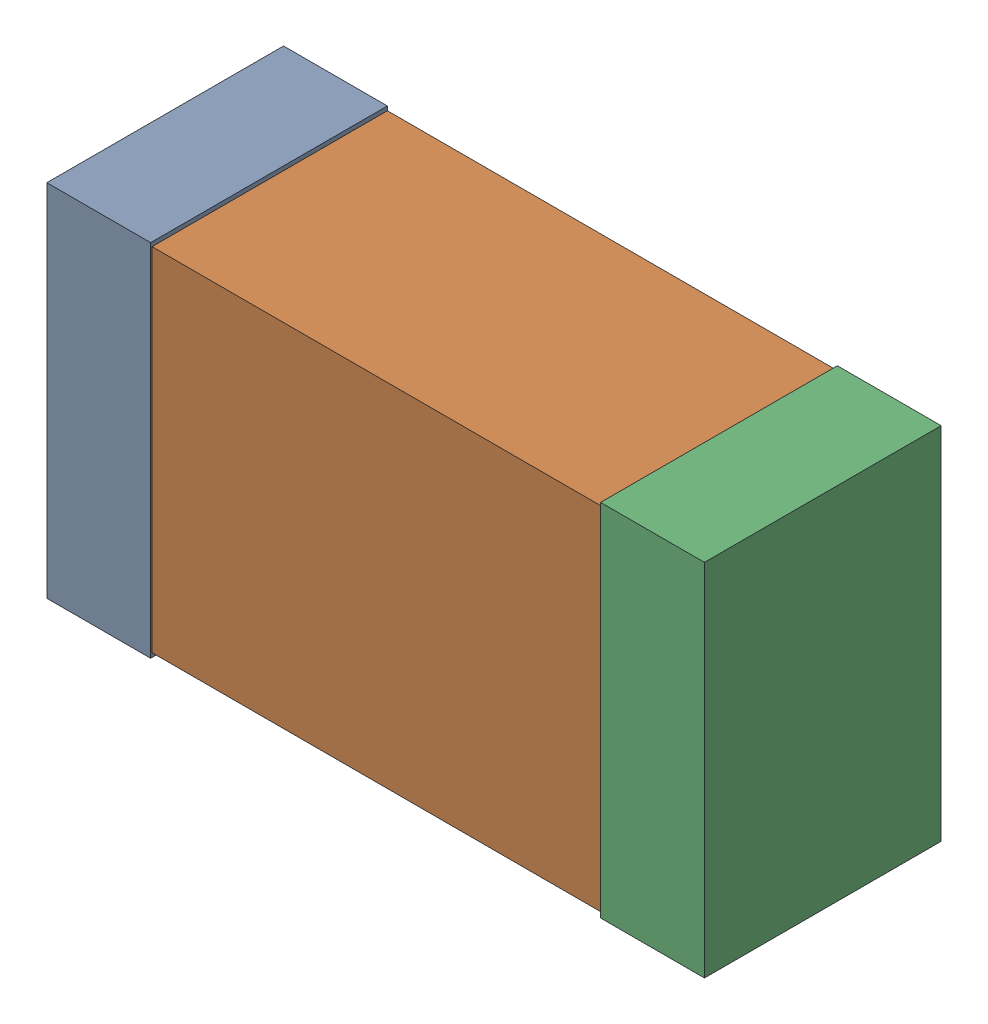
SolidWorks assembly R4Kanaloa_v2.0.0_Power, configuration Default. Lengths in mm.
Overall size (2.38 1.3 0.85).
6 component instances, 2 part files, 0 mates.
Components (placement in the parent):
- 352877648-1: 352877648 [Default] at (69.525 114.5 0) size (0.38 1.3 0.85)
  - Extruded_14-1: Extruded_14 [Default] at origin size (0.38 1.3 0.85)
- 352877904-1: 352877904 [Default] at (70.525 114.5 0) size (2.2 1.27 0.85)
  - Extruded_18-1: Extruded_18 [Default] at origin size (2.2 1.27 0.85)
- 352877648-2: 352877648 [Default] at (71.525 114.5 0) size (0.38 1.3 0.85)
  - Extruded_14-1: Extruded_14 [Default] at origin size (0.38 1.3 0.85)
